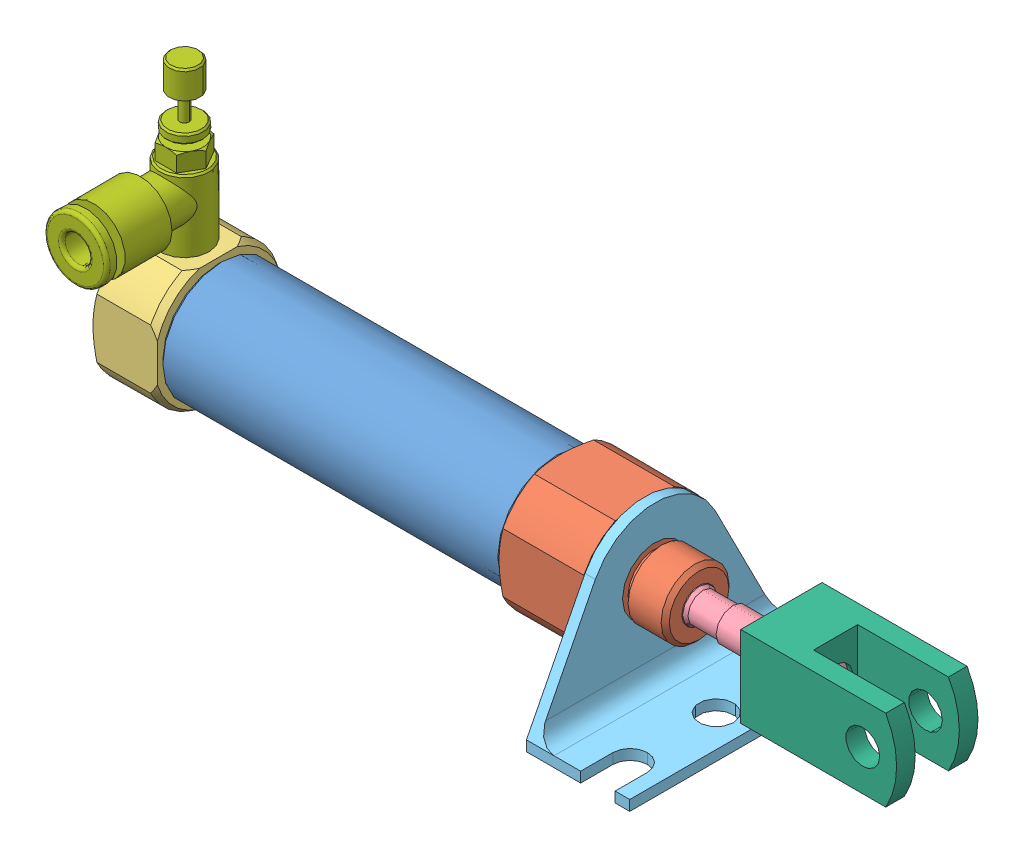
SolidWorks assembly Assem1, configuration Default. Lengths in mm.
Overall size (115.7 46.02 34.92).
10 component instances, 7 part files, 0 mates.
Components (placement in the parent):
- AirCylinder-1: AirCylinder [Default] at (27.6288 60.5422 78.6303) size (115.7 46.02 34.92)
  - NCJ22005Z-MP-1: NCJ22005Z-MP [Default] x (0 0 -1) z (1 0 0) size (34.92 23.88 100.4)
    - NCJ2Tubes-1: NCJ2Tubes [16] at origin size (17.4 17.4 50.4)
    - NCJ2RodCover-1: NCJ2RodCover [16] at (0 0 25.2) size (18 18 20.5)
    - NCJ2HeadCover-1: NCJ2HeadCover [16] at (0 0 -34.7) size (18 18 9.5)
    - NCJ2Rods-1: NCJ2Rods [16] at (0 0 -12.7) size (15.5 15.5 80.9)
    - pneumatic-cylinder-bracket-1: pneumatic-cylinder-bracket [Default] at (0 -13.97 37.7) size (34.92 23.88 15.24)
  - RodClevis-1: RodClevis [Default] at (75.85 0 0) size (23 12 12)
  - As3054-1: As3054 [Default] at (-30.2 15.45 0) x (0 0 -1) z (1 0 0) size (19.7 26.6 9.3)
    - AS3054 Body-1: AS3054 Body [12-M3-04] at origin size (19.7 26.6 9.3)
